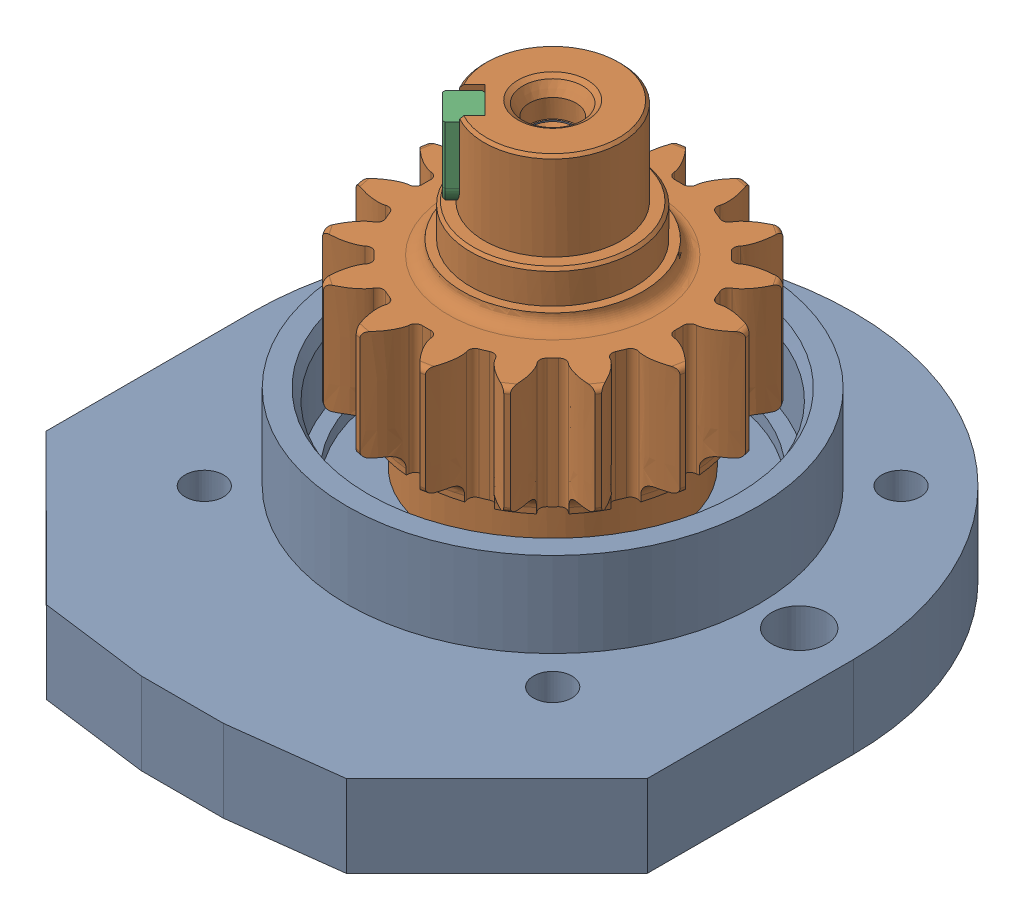
SolidWorks assembly g1_3_1_1_2_2, configuration 默认. Lengths in mm.
Overall size (219.6 152 245).
3 component instances, 3 part files, 0 mates.
Components (placement in the parent):
- g1_3_1_1_2-1_2-1: g1_3_1_1_2-1_2 [默认] at origin size (219.6 61 245)
- g1_3_1_1_2-2_2-1: g1_3_1_1_2-2_2 [默认] at (0 152 0) x (-0.047609 0 0.998866) z (0 1 0) size (120.16 120.16 117)
- g1_3_1_1_2-3_2-1: g1_3_1_1_2-3_2 [默认] at (-20.1525 129 20.1525) x (0 -1 0) z (0.707107 0 0.707107) size (28 11 14)
